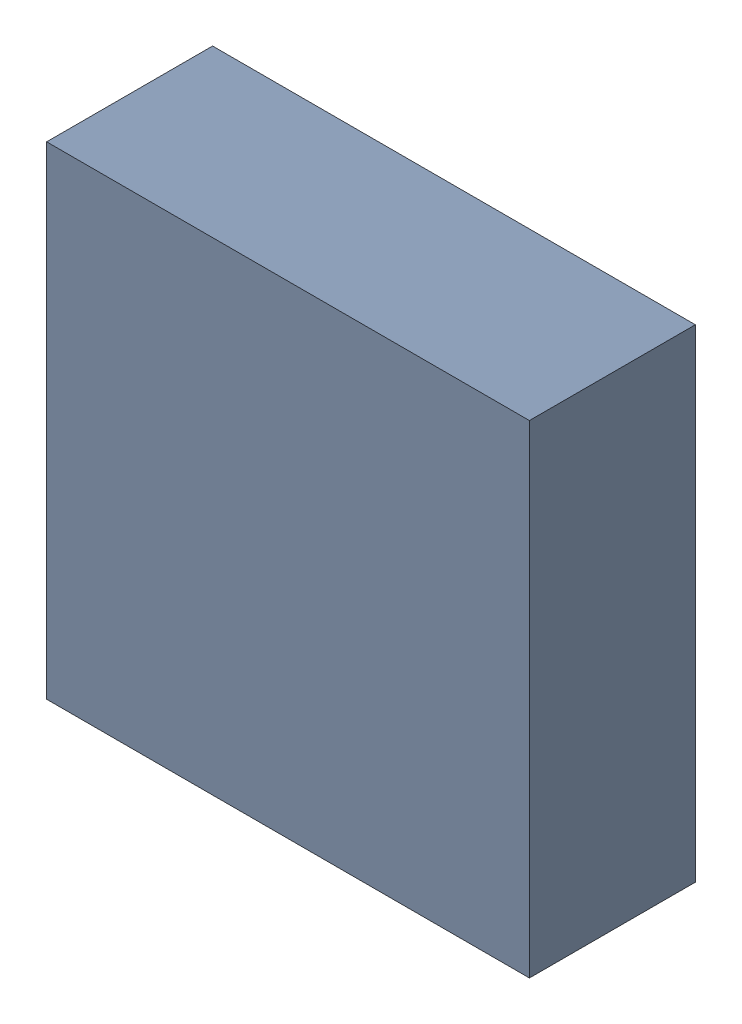
SolidWorks assembly U304_2PCB, configuration Default. Lengths in mm.
Overall size (3.2 3.2 1.1).
2 component instances, 1 part files, 0 mates.
Components (placement in the parent):
- 846484240-1: 846484240 [Default] at (132.35 96.1 0) size (3.2 3.2 1.1)
  - Extruded_11-1: Extruded_11 [Default] at origin size (3.2 3.2 1.1)
